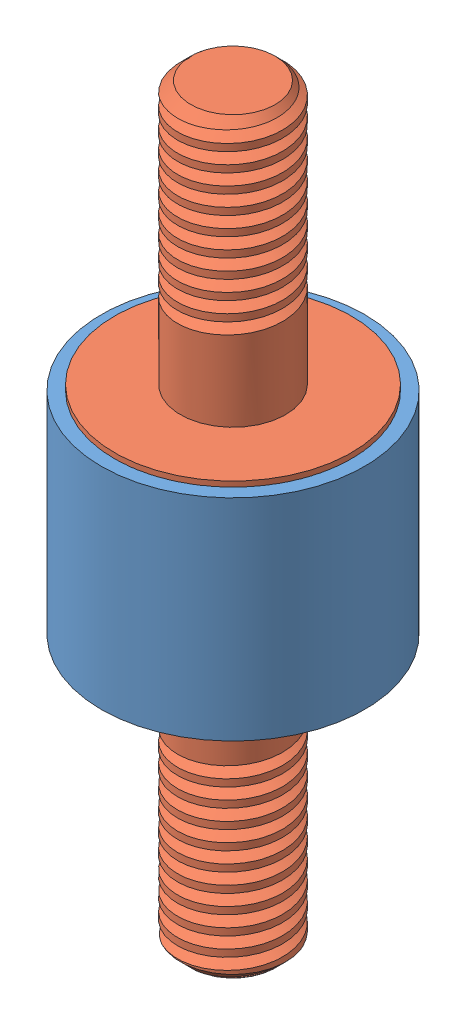
SolidWorks assembly VibrationDamper, configuration Default. Lengths in mm.
Overall size (11.69 28.63 11.69).
3 component instances, 2 part files, 6 mates.
Components (placement in the parent):
- VibrationDamper-Body-1: VibrationDamper-Body [Default] at (3.3623 0.614 8.282) size (10 8 10)
- VibrationDamper-bolt-1: VibrationDamper-bolt [Default] at (3.3623 7.814 8.282) x (0.37026 0 0.928928) z (-0.928928 0 0.37026) size (9 11.11 9)
- VibrationDamper-bolt-2: VibrationDamper-bolt [Default] at (3.3623 1.414 8.282) x (-1 0 0) z (0 0 1) size (9 11.11 9)
Mates (geometry in assembly coordinates):
- Coincidente1: coincident anti-aligned: plane of VibrationDamper-Body-1 through (3.3623 7.814 8.282) normal (0 1 0); plane of VibrationDamper-bolt-1 through (3.3623 7.814 8.282) normal (0 -1 0)
- Coincidente2: coincident aligned: circle of VibrationDamper-Body-1; circle of VibrationDamper-bolt-1
- Coincidente3: coincident anti-aligned: plane of VibrationDamper-Body-1 through (3.3623 1.414 8.282) normal (0 -1 0); plane of VibrationDamper-bolt-2 through (3.3623 1.414 8.282) normal (0 1 0)
- Coincidente4: coincident aligned: circle of VibrationDamper-Body-1; circle of VibrationDamper-bolt-2
- Blocca1: lock: unknown of VibrationDamper-bolt-2; unknown of VibrationDamper-Body-1
- Blocca2: lock: unknown of VibrationDamper-bolt-2; unknown of VibrationDamper-bolt-1
